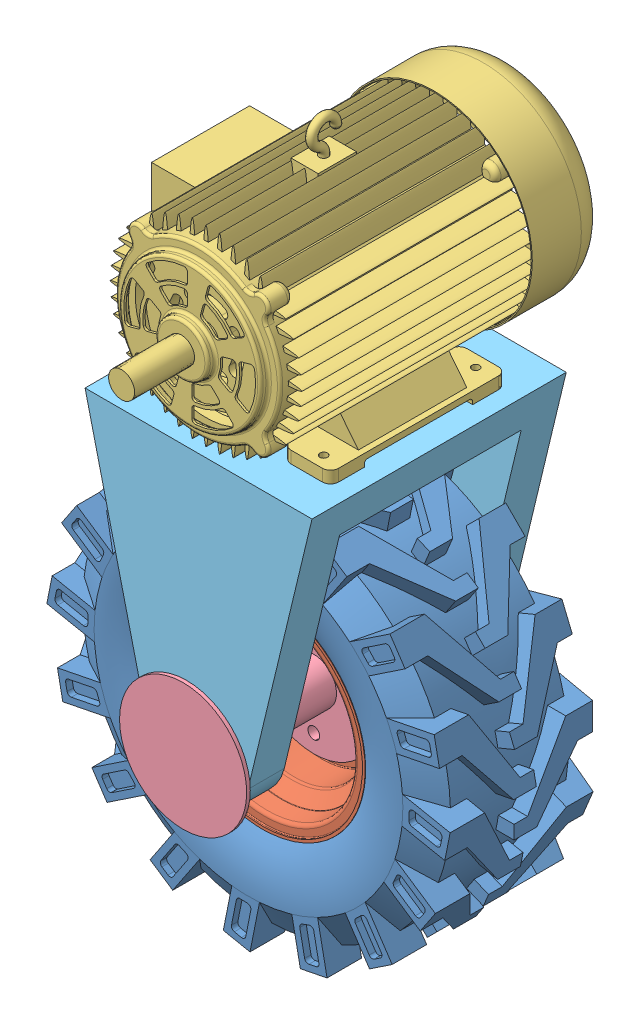
SolidWorks assembly wheel, configuration Default. Lengths in mm.
Overall size (444.2 759 428.4).
6 component instances, 5 part files, 10 mates.
Components (placement in the parent):
- AS-16x6.50-8-00 v4.step-1: AS-16x6.50-8-00 v4.step [Default] at origin size (444.2 444.2 172.6)
  - AS-16x6.50-8-01.step-1: AS-16x6.50-8-01.step [Default] at origin size (444.2 444.2 172.6)
  - 5.50A-8-00.step-1: 5.50A-8-00.step [Default] at origin size (226.84 226.84 139.7)
- 01-143-405- ELECTRIC MOTOR-1: 01-143-405- ELECTRIC MOTOR [Default] at (0 388 -86.091) size (243.6 256.9 428.4)
- Shaft-1: Shaft [Default] at (0 0 -75.2503) x (-1 0 0) z (0 0 -1) size (140 140 304)
- Bracket-1: Bracket [Default] at (0 0 -88.2503) size (250 336 280)
Mates (geometry in assembly coordinates):
- Coincident1: coincident anti-aligned: plane of AS-16x6.50-8-00 v4.step-1/5.50A-8-00.step-1 through (0 30 -85.2503) normal (0 0 1); plane of Shaft-1 through (0 0 -85.2503) normal (0 0 -1)
- Concentric1: concentric aligned: cylinder of AS-16x6.50-8-00 v4.step-1/5.50A-8-00.step-1 through (0 0 -89.7503) axis (0 0 -1) radius 30; cylinder of Shaft-1 through (0 0 64.7497) axis (0 0 -1) radius 25
- Concentric2: concentric aligned: circle of AS-16x6.50-8-00 v4.step-1/5.50A-8-00.step-1; cylinder of Shaft-1 through (0 -50 -85.2503) axis (0 0 1) radius 6.5
- Concentric3: concentric: axis of ? through (0 0 -107.2928) axis (0 0 1); cylinder of Bracket-1 through (0 0 51.7497) axis (0 0 -1) radius 26
- Width1: width aligned: plane of Bracket-1 through (0 0 -228.2503) normal (0 0 -1); plane of AS-16x6.50-8-00 v4.step-1/5.50A-8-00.step-1 through (0 0 51.7497) normal (0 0 1); plane of Bracket-1 through (0 99.1198 -155.6003) normal (0 0 -1); plane of AS-16x6.50-8-00 v4.step-1/5.50A-8-00.step-1 through (0 99.1198 -20.9003) normal (0 0 1)
- Parallel1: parallel aligned: plane of Bracket-1 through (0 280 51.7497) normal (0 1 0)
- Coincident3: coincident: plane of 01-143-405- ELECTRIC MOTOR-1 through (0 280 -86.091) normal (0 -1 0); plane of Bracket-1 through (0 280 51.7497) normal (0 1 0)
- Parallel2: parallel: plane of 01-143-405- ELECTRIC MOTOR-1 through (0 388 136.509) normal (0 0 1); plane of Bracket-1 through (0 0 51.7497) normal (0 0 1)
- Width2: width: plane of 01-143-405- ELECTRIC MOTOR-1 through (-104.4 293.2 -182.991) normal (-1 0 0); plane of Bracket-1 through (104.4 293.2 -182.991) normal (1 0 0); plane of 01-143-405- ELECTRIC MOTOR-1 through (54.4448 -13.1057 51.7497) normal (0.972229 -0.234031 0); plane of Bracket-1 through (-54.4448 -13.1057 51.7497) normal (-0.972229 -0.234031 0)
- Distance1: distance = 67.7593 mm aligned: plane of 01-143-405- ELECTRIC MOTOR-1 through (0 388 136.509) normal (0 0 1); plane of Shaft-1 through (0 0 68.7497) normal (0 0 1)
